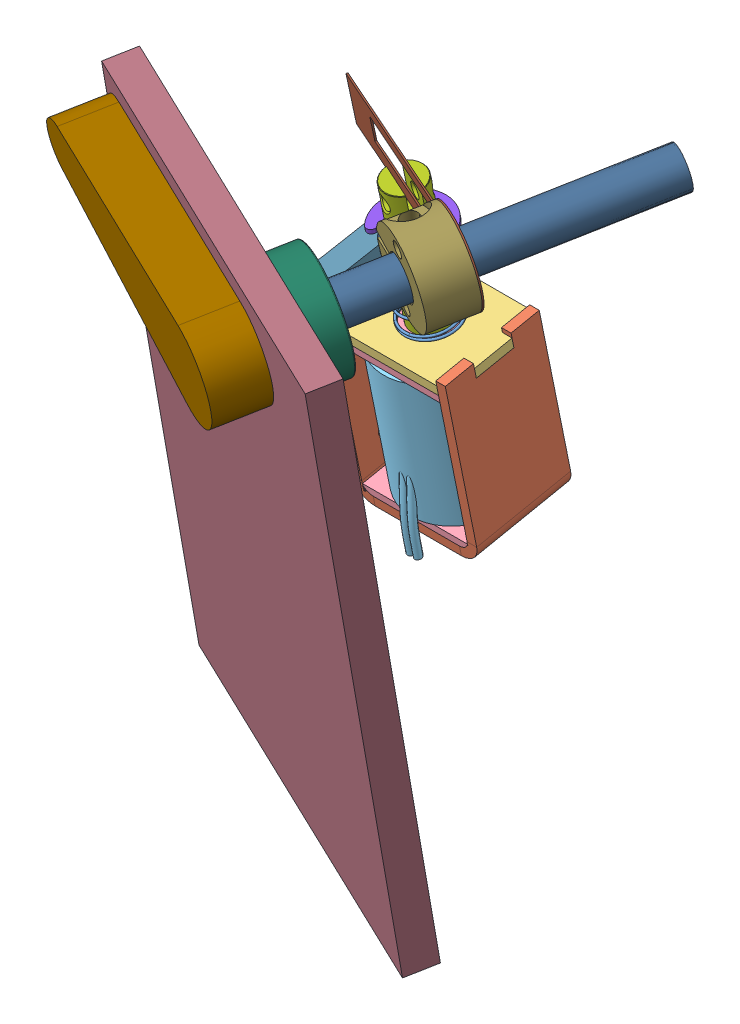
SolidWorks assembly flipper assembly, configuration Default. Lengths in mm.
Overall size (84.92 136.5 81.28).
17 component instances, 15 part files, 11 mates.
Components (placement in the parent):
- 0837 solenoid.stp-1: 0837 solenoid.stp [Default] at origin size (26 70.22 30.6)
  - Пружина сжатия.stp-1: Пружина сжатия.stp [Default] at (13 68.781 -203.166) x (-0.985424 -0.033783 0.166729) z (-0.170117 0.19569 -0.965798) size (11.59 18.02 11.65)
    - Пружина сжатия1.stp-1: Пружина сжатия1.stp [Default] at origin size (11.59 18.02 11.65)
  - base.stp-1: base.stp [Default] at (13 33.9516 -210.2231) x (1 0 0) z (0 0.198584 -0.980084) size (26 37 20)
  - cover.stp-1: cover.stp [Default] at (13 67.2745 -203.4712) x (0 -0.980084 -0.198584) z (-1 0 0) size (2 20 26)
  - frame.stp-1: frame.stp [Default] at (13 33.9516 -210.2231) x (0 0.980084 0.198584) z (0 0.198584 -0.980084) size (34 22 20)
  - coil.stp-1: coil.stp [Default] at (-6.5145 14.7377 -201.7104) x (-0.999808 -0.003892 0.019207) z (0.019597 -0.198546 0.979896) size (21.92 36.15 23.47)
  - nut.stp-1: nut.stp [Default] at (60.4092 27.3165 -162.6494) x (-0.703131 0.141205 -0.696899) z (-0.71106 -0.139631 0.689127) size (8 6 8)
  - kern.stp-1: kern.stp [Default] at (13 54.0999 -206.1407) x (0.386326 0.183167 -0.903992) z (0.922362 -0.076718 0.378632) size (8.04 42 8)
  - DIN 6799 - 7.stp-1: DIN 6799 - 7.stp [Default] at (12.4621 87.225 -203.4487) x (-0.990807 -0.026865 0.132588) z (0 -0.980084 -0.198584) size (14.3 11.59 0.9)
- Flipper-1: Flipper [Défaut] at (25.9085 83.236 -157.6784) x (-0.90764 0.249903 -0.33725) z (-0.386326 -0.183167 0.903992) size (60.25 19.29 10)
- rod-1: rod [Default] at (43.6479 98.8569 -225.2745) x (0.901605 0.131764 0.412004) z (-0.386326 -0.183167 0.903992) size (8 8 80)
- paddle brace 2-1: paddle brace 2 [Default] at (29.7074 92.2473 -192.654) x (0.921613 -0.037165 0.386326) z (-0.386326 -0.183167 0.903992) size (50.38 18 0.32)
- 8mm_shaft_collar-1: 8mm_shaft_collar [Default] at (26.1078 90.5407 -184.2311) x (0.916711 -0.184571 0.354364) z (0.101943 0.9656 0.239215) size (18 9 18)
- platform-1: platform [Default] at (-26.0553 107.6429 -181.7267) x (-0.066207 -0.972049 -0.22525) z (-0.386326 -0.183167 0.903992) size (127.74 76.3 6.13)
- solenoid mount-2: solenoid mount [Default] at (-4.9769 68.8702 -183.9792) x (0 -0.983678 -0.179937) z (1 0 0) size (40 25 20)
- 8mm Bearing SKF 608 (RS 286-7530)-1: 8mm Bearing SKF 608 (RS 286-7530) [Default] at (21.3624 88.2908 -173.127) x (0.386326 0.183167 -0.903992) z (0.921639 -0.037868 0.386195) size (7 22 22)
Mates (geometry in assembly coordinates):
- Concentric1: concentric anti-aligned: cylinder of rod-1 through (12.7418 84.2035 -152.9551) axis (0.386326 0.183167 -0.903992) radius 4; circle of paddle brace 2-1
- Concentric4: concentric aligned: cylinder of Flipper-1 through (13.1974 84.4195 -154.0212) axis (0.386326 0.183167 -0.903992) radius 3.55; cylinder of rod-1 through (12.7418 84.2035 -152.9551) axis (0.386326 0.183167 -0.903992) radius 4
- Coincident1: coincident anti-aligned: plane of 0837 solenoid.stp-1/kern.stp-1 through (9.7047 95.8066 -200.4811) normal (-0.386326 -0.183167 0.903992); plane of paddle brace 2-1 through (29.7074 92.2473 -192.654) normal (0.386326 0.183167 -0.903992)
- Coincident3: coincident anti-aligned: circle of paddle brace 2-1; plane of 8mm_shaft_collar-1 through (29.5847 92.1892 -192.367) normal (0.386326 0.183167 -0.903992)
- Concentric11: concentric anti-aligned: cylinder of rod-1 through (12.7418 84.2035 -152.9551) axis (0.386326 0.183167 -0.903992) radius 4; cylinder of 8mm_shaft_collar-1 through (29.5847 92.1892 -192.367) axis (-0.386326 -0.183167 0.903992) radius 4.25
- Concentric12: concentric anti-aligned: cylinder of rod-1 through (12.7418 84.2035 -152.9551) axis (0.386326 0.183167 -0.903992) radius 4; cylinder of platform-1 through (18.6581 87.0086 -166.7991) axis (-0.386326 -0.183167 0.903992) radius 4.5
- Coincident4: coincident anti-aligned: plane of Flipper-1 through (17.1524 85.6469 -160.9319) normal (0.386326 0.183167 -0.903992); plane of platform-1 through (-28.4254 106.5192 -176.1807) normal (-0.386326 -0.183167 0.903992)
- Concentric13: concentric aligned: cylinder of 0837 solenoid.stp-1/base.stp-1 through (4.4 62.1883 -208.5831) axis (-1 0 0) radius 1.2295; cylinder of solenoid mount-2 through (0.0231 62.1883 -208.5831) axis (-1 0 0) radius 1
- Parallel3: parallel aligned: cylinder of 0837 solenoid.stp-1/base.stp-1 through (4.4 42.5867 -212.5548) axis (-1 0 0) radius 1.2295; cylinder of solenoid mount-2 through (0.0231 44.4821 -211.822) axis (-1 0 0) radius 1
- Concentric15: concentric aligned: cylinder of rod-1 through (12.7418 84.2035 -152.9551) axis (0.386326 0.183167 -0.903992) radius 4; cylinder of 8mm Bearing SKF 608 (RS 286-7530)-1 through (21.3624 88.2908 -173.127) axis (0.386326 0.183167 -0.903992) radius 4
- Coincident5: coincident anti-aligned: plane of platform-1 through (-26.0553 107.6429 -181.7267) normal (0.386326 0.183167 -0.903992); plane of 8mm Bearing SKF 608 (RS 286-7530)-1 through (18.3476 95.3635 -165.2389) normal (-0.386326 -0.183167 0.903992)
